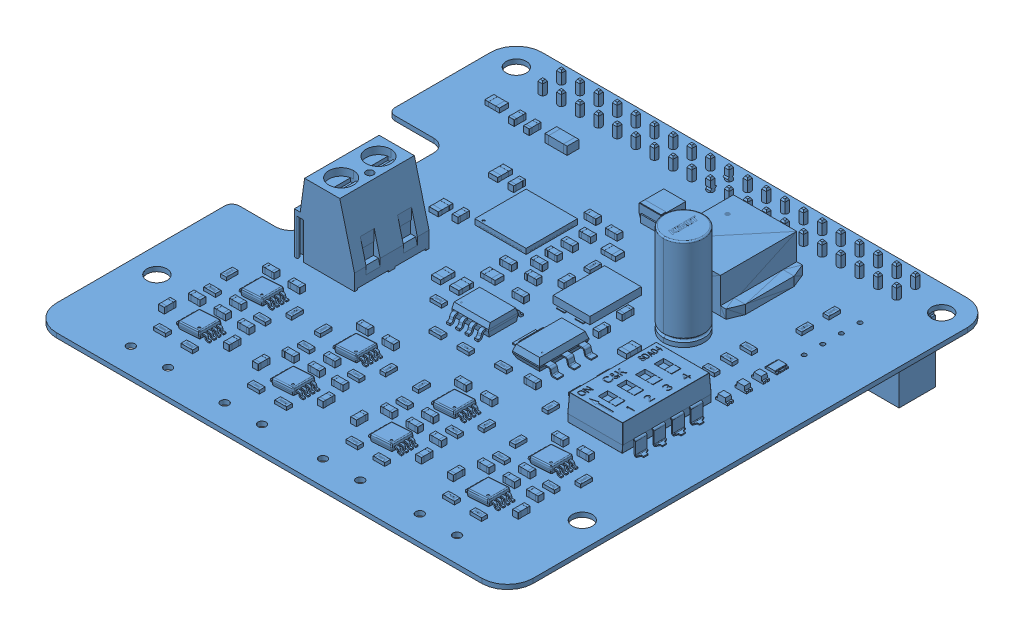
SolidWorks assembly pcbWithPi, configuration Default. Lengths in mm.
Overall size (64.99 32.52 66.2).
2 component instances, 2 part files, 3 mates.
Components (placement in the parent):
- Top-2: Top [Default] at (-4.2348 44.5064 41.2898) x (1 0 0) z (0 1 0) size (64.99 66.2 32.52)
- Raspberry Pi 3-2: Raspberry Pi 3 [Default] at (54.2115 28.8209 -21.0547) x (1 0 0) z (0 1 0) (suppressed, hidden)
Mates (geometry in assembly coordinates):
- Coincident1: coincident aligned: plane of Top-2 through (13.8195 46.2829 -48.7426) normal (-1 0 0); plane of Raspberry Pi 3-2 through (13.8195 32.3109 -49.3876) normal (-1 0 0)
- Coincident2: coincident aligned: plane of Top-2 through (13.8195 46.2829 -49.3776) normal (0 0 -1); plane of Raspberry Pi 3-2 through (14.4695 32.3109 -49.3776) normal (0 0 -1)
- Distance1: distance = 0.5 mm anti-aligned: plane of Top-2 through (63.921 32.8209 -47.7901) normal (0 -1 0); plane of Raspberry Pi 3-2 through (12.8595 32.3209 -45.4554) normal (0 1 0)
